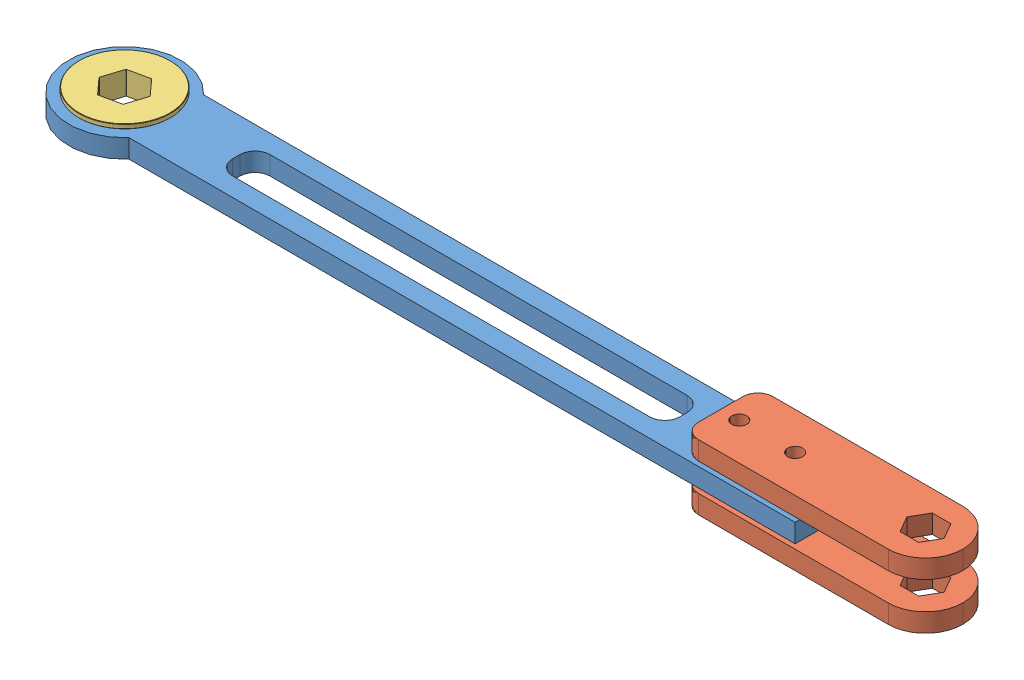
SolidWorks assembly A400 Link, configuration Default. Lengths in mm.
Overall size (304.8 22.23 38.1).
4 component instances, 3 part files, 5 mates.
Components (placement in the parent):
- A401 Aluminum Bar-1: A401 Aluminum Bar [Default] at origin size (260.35 6.35 38.1)
- A402 Bar Clevis Plate-1: A402 Bar Clevis Plate [Default] at (130.175 7.9375 0) x (0 1 0) z (-1 0 0) size (6.35 25.4 82.55)
- A402 Bar Clevis Plate-2: A402 Bar Clevis Plate [Default] at (130.175 -7.9375 0) x (0 1 0) z (-1 0 0) size (6.35 25.4 82.55)
- am-2986 FR8ZZ Hex Bearing.step-1: am-2986 FR8ZZ Hex Bearing.step [Default] at (-114.3 -3.175 0) x (0.977149 0 -0.212557) z (0 1 0) size (31.12 31.12 7.93)
Mates (geometry in assembly coordinates):
- Distance2: distance = 1.5875 mm anti-aligned: plane of Aluminum Bar-1 through (0 3.175 0) normal (0 1 0); plane of A402 Bar Clevis Plate-1 through (130.175 4.7625 0) normal (0 -1 0)
- Concentric1: concentric aligned: cylinder of Aluminum Bar-1 through (95.25 3.175 0) axis (0 1 0) radius 2.5527; cylinder of A402 Bar Clevis Plate-1 through (95.25 11.1125 0) axis (0 1 0) radius 2.5527
- Concentric2: concentric aligned: cylinder of Aluminum Bar-1 through (114.3 3.175 0) axis (0 1 0) radius 2.5527; cylinder of A402 Bar Clevis Plate-1 through (114.3 11.1125 0) axis (0 1 0) radius 2.5527
- Concentric3: concentric aligned: cylinder of Aluminum Bar-1 through (-114.3 3.175 0) axis (0 -1 0) radius 14.2875; cylinder of am-2986 FR8ZZ Hex Bearing.step-1 through (-114.3 4.7523 0) axis (0 -1 0) radius 14.2875
- Coincident2: coincident aligned: plane of Aluminum Bar-1 through (0 -3.175 0) normal (0 -1 0); plane of am-2986 FR8ZZ Hex Bearing.step-1 through (-114.3 -3.175 0) normal (0 -1 0)
